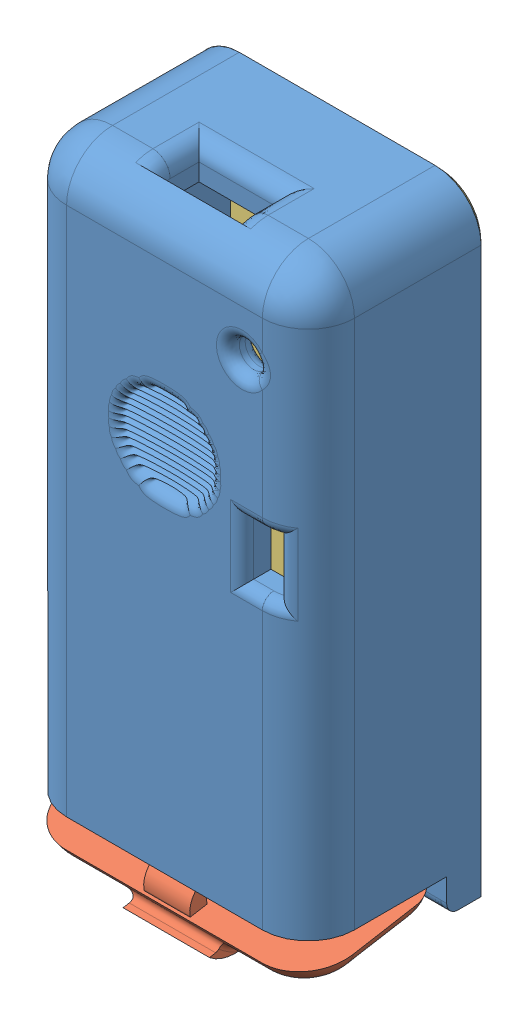
SolidWorks assembly Assembly_final, configuration Default. Lengths in mm.
Overall size (50.86 111.03 34.38).
3 component instances, 3 part files, 7 mates.
Components (placement in the parent):
- box_new_version-1: box_new_version [Default] at (12.5298 48.6978 100.1279) size (50 106 31.16)
- cover_earplugs-1: cover_earplugs [Default] at (13.5298 -9.5566 99.3933) x (1 0 0) z (0 -0.171623 0.985163) size (50.86 10.01 31.14)
- Tampa-1: Tampa [Default] at (12.5298 45.6978 82.6279) size (50 106 2.5)
Mates (geometry in assembly coordinates):
- Coincident4: coincident: box_new_version-1, Tampa-1
- Coincident5: coincident: box_new_version-1, Tampa-1
- Concentric1: concentric: box_new_version-1, cover_earplugs-1
- Coincident9: coincident: box_new_version-1, cover_earplugs-1
- Distance2: distance: cover_earplugs-1, box_new_version-1
- Coincident10: coincident: box_new_version-1, Tampa-1
- Concentric2: concentric: box_new_version-1, cover_earplugs-1
